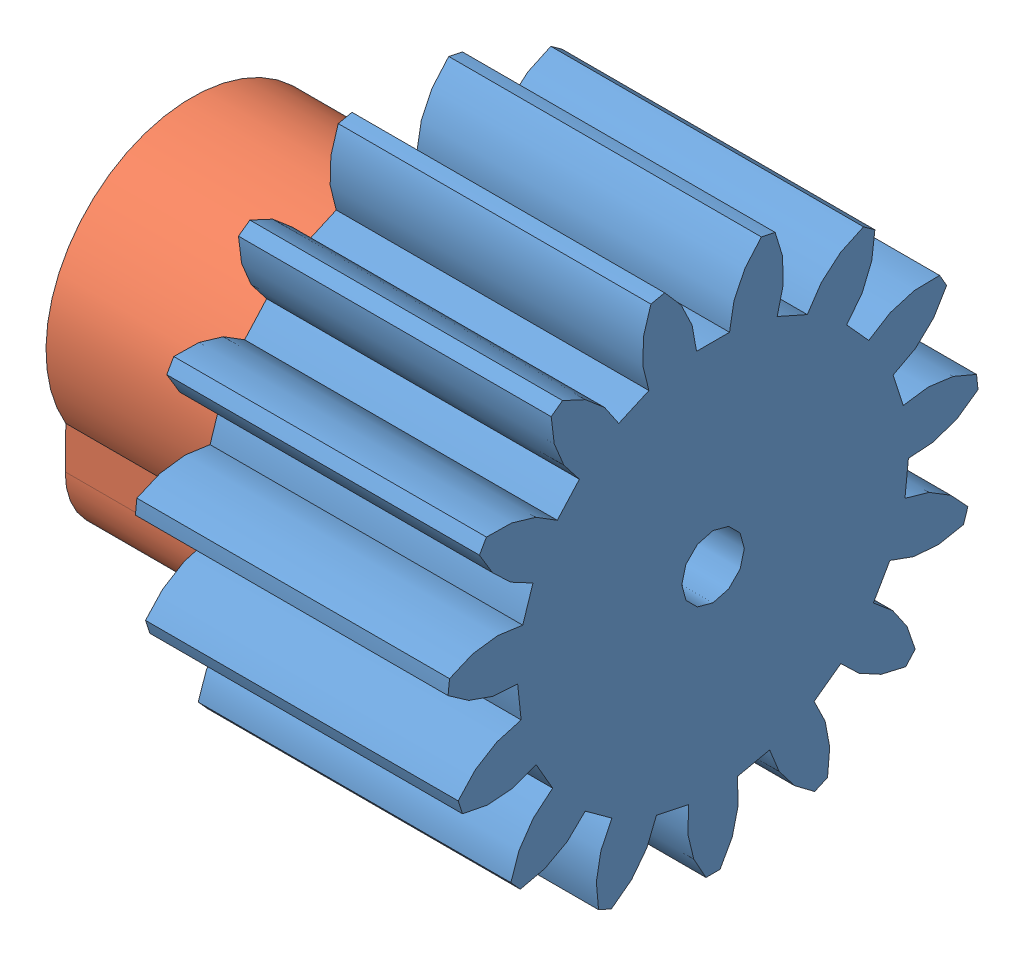
SolidWorks assembly Assem1, configuration Default. Lengths in mm.
Overall size (25 25.29 25.42).
2 component instances, 2 part files, 2 mates.
Components (placement in the parent):
- spur gear_iso-bandap-1: spur gear_iso-bandap [ISO - Spur gear 1.5M 15T 20PA 15FW ---S15A75H50L3.0N] at (-26.2047 2.0539 8.5472) size (15 25.29 25.42)
- gear-bandapAssistant-1: gear-bandapAssistant [Default] at (-19.2047 4.0901 8.6828) x (0 0 1) z (-1 0 0) size (14 16.14 17)
Mates (geometry in assembly coordinates):
- Concentric2: concentric aligned: circle of spur gear_iso-bandap-1; circle of gear-bandapAssistant-1
- Coincident1: coincident anti-aligned: plane of spur gear_iso-bandap-1 through (-26.2047 2.0539 8.5472) normal (-1 0 0); plane of gear-bandapAssistant-1 through (-26.2047 4.0901 8.6828) normal (1 0 0)
